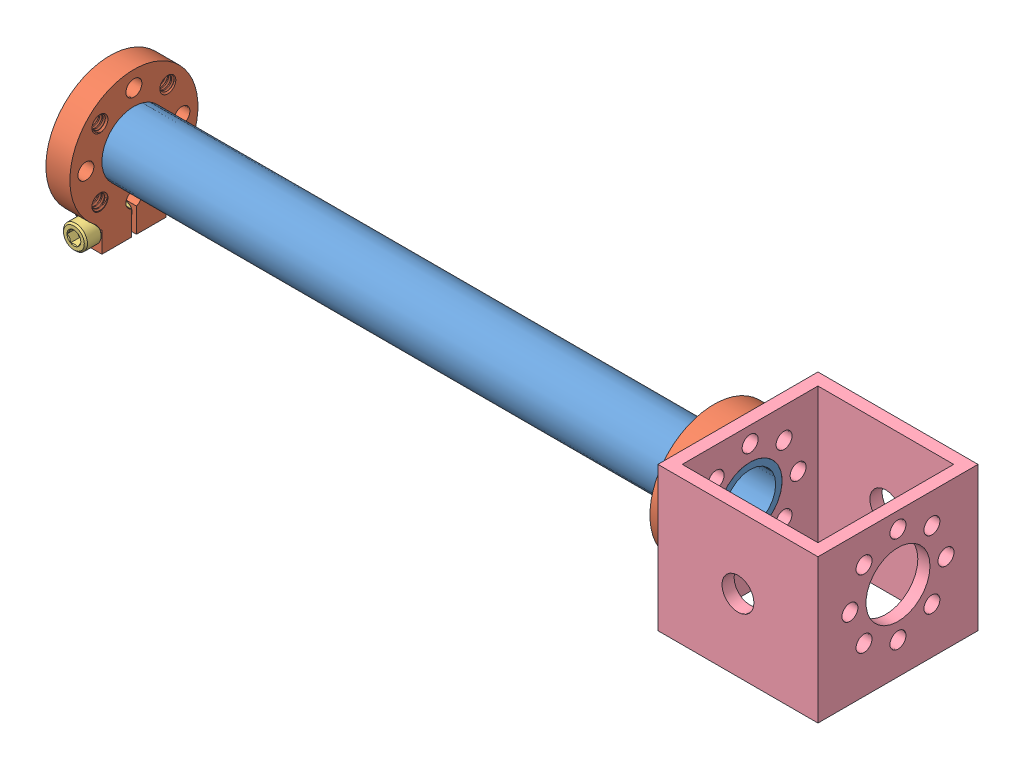
SolidWorks assembly subassem_rightlink, configuration Default. Lengths in mm.
Overall size (312.87 60.57 63.5).
8 component instances, 4 part files, 9 mates.
Components (placement in the parent):
- tubing1rl-1: tubing1rl [Default<As Machined>] at (32.4558 163.244 220.4128) size (254 25.4 25.4)
- Clamping hub 1inch-1: Clamping hub 1inch [Default] at (14.6195 139.1097 289.2058) x (0 0 1) z (0 1 0) size (50.8 9.91 57.17)
  - 545356-1: 545356 [Default] at (-68.793 17.8362 24.1343) size (50.8 9.91 57.17)
  - 91251A542_91251A542-1: 91251A542_91251A542 [Default] at (-81.493 22.5987 -1.2123) x (0 0 1) z (-1 0 0) size (9.53 9.53 32.08)
- Clamping hub 1inch-2: Clamping hub 1inch [Default] at (299.466 139.1097 151.6198) x (0 0 -1) z (0 1 0) size (50.8 9.91 57.17)
  - 545356-1: 545356 [Default] at (-68.793 17.8362 24.1343) size (50.8 9.91 57.17)
  - 91251A542_91251A542-1: 91251A542_91251A542 [Default] at (-81.493 22.5987 -1.2123) x (0 0 1) z (-1 0 0) size (9.53 9.53 32.08)
- right_block-1: right_block [Default] at (345.1298 163.244 220.4128) x (0 0 1) z (-1 0 0) size (63.5 57.15 63.5)
Mates (geometry in assembly coordinates):
- Concentric1: concentric anti-aligned: circle of tubing1rl-1; cylinder of Clamping hub 1inch-1/545356-1 through (41.9808 163.244 220.4128) axis (-1 0 0) radius 12.7
- Parallel1: parallel anti-aligned: line of Clamping hub 1inch-1/545356-1 through (32.4558 141.186 219.3968) axis (0 -1 0); line of assembly
- Coincident4: coincident aligned: plane of tubing1rl-1 through (32.4558 163.244 220.4128) normal (-1 0 0); plane of Clamping hub 1inch-1/545356-1 through (32.4558 163.244 220.4128) normal (-1 0 0)
- Concentric2: concentric anti-aligned: cylinder of tubing1rl-1 through (286.4558 163.244 220.4128) axis (-1 0 0) radius 12.7; cylinder of Clamping hub 1inch-2/545356-1 through (276.9308 163.244 220.4128) axis (1 0 0) radius 12.7
- Parallel2: parallel anti-aligned: line of Clamping hub 1inch-1/545356-1 through (41.9808 141.186 219.3968) axis (0 -1 0); line of Clamping hub 1inch-2/545356-1 through (286.4558 131.4712 219.3968) axis (0 1 0)
- Concentric3: concentric aligned: cylinder of Clamping hub 1inch-2/545356-1 through (276.9308 182.294 220.4128) axis (-1 0 0) radius 3.175; cylinder of right_block-1 through (291.2818 182.294 220.4128) axis (-1 0 0) radius 3.175
- Concentric4: concentric aligned: cylinder of Clamping hub 1inch-2/545356-1 through (276.9308 163.244 239.4628) axis (-1 0 0) radius 3.175; cylinder of right_block-1 through (291.2818 163.244 239.4628) axis (-1 0 0) radius 3.175
- Coincident6: coincident anti-aligned: plane of Clamping hub 1inch-2/545356-1 through (286.4558 163.244 220.4128) normal (1 0 0); plane of right_block-1 through (286.4558 163.244 220.4128) normal (-1 0 0)
- Coincident7: coincident aligned: plane of tubing1rl-1 through (286.4558 163.244 220.4128) normal (1 0 0); plane of right_block-1 through (286.4558 163.244 220.4128) normal (1 0 0)
